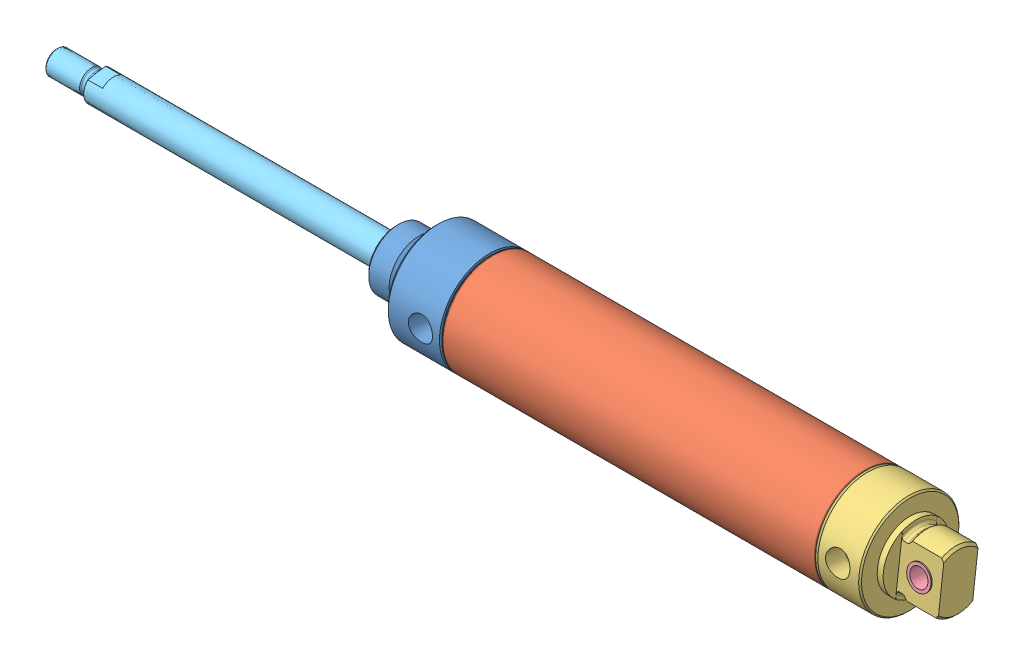
SolidWorks assembly 316-DXP_2_14, configuration Default. Lengths in mm.
Overall size (476.24 59.03 59.03).
5 component instances, 5 part files, 8 mates.
Components (placement in the parent):
- _31R000-0_rod_guide-1: _31R000-0_rod_guide [Default] at (0.2012 0.858 -0.4187) size (58.72 52.97 52.97)
- _31R-7.7870-1: _31R-7.7870 [Default] at (50.4551 0.858 -0.4187) size (199.7 52.97 52.97)
- _31P0Y000_rear_head-1: _31P0Y000_rear_head [Default] at (241.3742 0.858 -0.4187) x (1 0 0) z (0 0.121734 0.992563) size (55.58 52.97 52.97)
- _D-624-5-1: _D-624-5 [Default] at (285.8242 0.885 -0.1982) x (1 0 0) z (0 -0.121734 -0.992563) size (12.76 12.76 19.05)
- _316-DXP0_rod-1: _316-DXP0_rod [Default] at (-147.5403 0.858 -0.4187) x (1 0 0) z (0 0.986881 0.161447) size (272.92 51.04 51.04)
Mates (geometry in assembly coordinates):
- Concentric1: concentric aligned: cylinder of _31R000-0_rod_guide-1 through (58.926 0.858 -0.4187) axis (-1 0 0) radius 26.4858; cylinder of _31R-7.7870-1 through (248.2449 0.858 -0.4187) axis (-1 0 0) radius 26.4858
- Coincident1: coincident aligned: cone of _31R000-0_rod_guide-1 through (50.8487 0.858 -0.4187) axis (-1 0 0); cone of _31R-7.7870-1 through (50.6241 0.858 -0.4187) axis (-1 0 0)
- Concentric3: concentric aligned: cylinder of _31R-7.7870-1 through (248.2449 0.858 -0.4187) axis (-1 0 0) radius 26.4858; cylinder of _31P0Y000_rear_head-1 through (271.5748 0.858 -0.4187) axis (-1 0 0) radius 26.4858
- Coincident2: coincident aligned: cone of _31R-7.7870-1 through (248.0758 0.858 -0.4187) axis (1 0 0); cone of _31P0Y000_rear_head-1 through (247.8513 0.858 -0.4187) axis (1 0 0)
- Concentric4: concentric anti-aligned: cylinder of _31P0Y000_rear_head-1 through (285.8242 2.5219 13.148) axis (0 0.121734 0.992563) radius 6.3818; cylinder of _D-624-5-1 through (285.8242 2.0445 9.256) axis (0 -0.121734 -0.992563) radius 6.3818
- Distance1: distance = 0.635 mm aligned: plane of _31P0Y000_rear_head-1 through (274.699 54.545 2.1773) normal (0 0.121734 0.992563); plane of _D-624-5-1 through (285.8242 -2.7077 9.8389) normal (0 0.121734 0.992563)
- Concentric5: concentric aligned: cylinder of _31R000-0_rod_guide-1 through (58.926 0.858 -0.4187) axis (-1 0 0) radius 26.4858; cylinder of _316-DXP0_rod-1 through (-157.0653 0.858 -0.4187) axis (-1 0 0) radius 6.35
- LimitDistance1: limit distance = 4.6586 mm anti-aligned: plane of _316-DXP0_rod-1 through (63.5845 2.1395 -8.2521) normal (-1 0 0); plane of _31R000-0_rod_guide-1 through (58.926 25.6674 -0.4187) normal (1 0 0)
